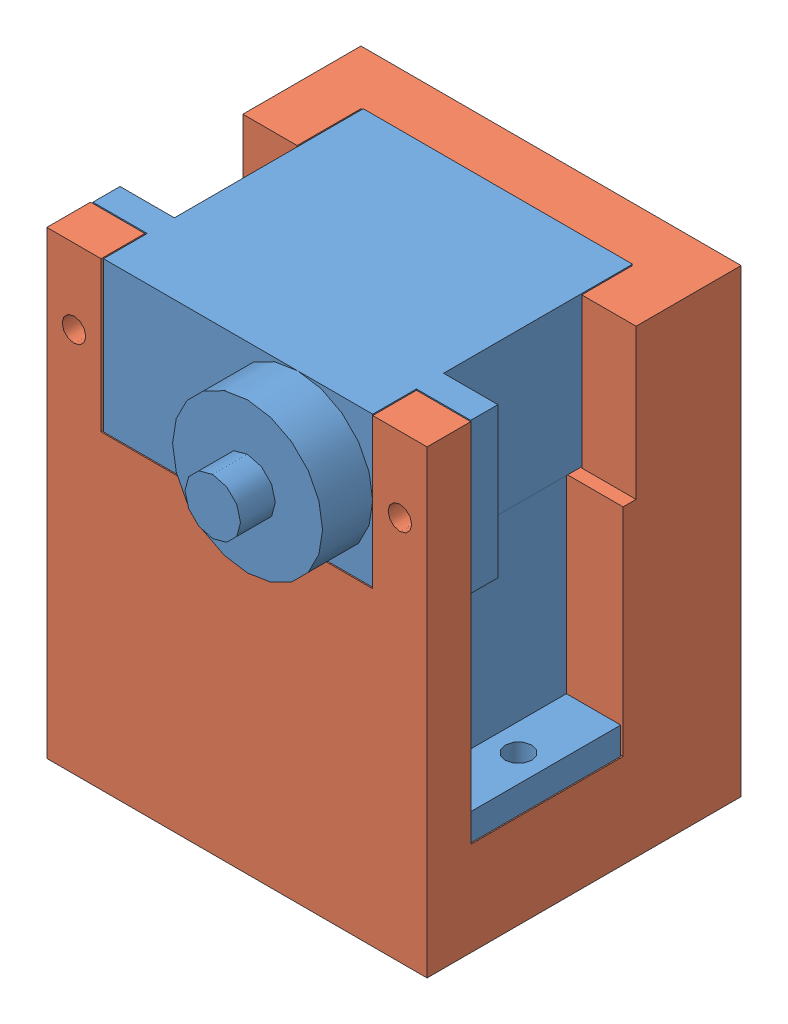
SolidWorks assembly Shoulder, configuration Default. Lengths in mm.
Overall size (32.2 41.9 33.7).
3 component instances, 2 part files, 7 mates.
Components (placement in the parent):
- SG92rMicroServo-1: SG92rMicroServo [Default] at (9.5187 30.2676 26.5439) x (1 0 0) z (0 -1 0) size (32 12.7 29.2)
- SG92rMicroServo-2: SG92rMicroServo [Default] at (9.5187 36.6176 14.5939) size (32 12.7 29.2)
- ShoulderStructure-1: ShoulderStructure [Default] at (14.5687 8.2676 26.5439) size (32.2 38.95 26.6)
Mates (geometry in assembly coordinates):
- Parallel1: parallel anti-aligned: plane of SG92rMicroServo-1 through (9.5187 30.2676 26.5439) normal (0 1 0); plane of SG92rMicroServo-2 through (-1.8813 30.2676 36.5939) normal (0 -1 0)
- Coincident4: coincident aligned: plane of SG92rMicroServo-1 through (-1.8813 8.2676 32.8939) normal (0 0 1); plane of SG92rMicroServo-2 through (9.5187 36.6176 32.8939) normal (0 0 1)
- Coincident5: coincident aligned: plane of SG92rMicroServo-1 through (20.9187 8.2676 20.1939) normal (1 0 0); plane of SG92rMicroServo-2 through (20.9187 30.2676 36.5939) normal (1 0 0)
- Coincident6: coincident anti-aligned: plane of SG92rMicroServo-1 through (9.5187 30.2676 26.5439) normal (0 1 0); plane of SG92rMicroServo-2 through (-1.8813 30.2676 36.5939) normal (0 -1 0)
- Concentric1: concentric aligned: cylinder of SG92rMicroServo-1 through (14.5687 -34.7792 26.5439) axis (0 1 0) radius 2.35; circle of ShoulderStructure-1
- Coincident7: coincident anti-aligned: plane of SG92rMicroServo-1 through (9.5187 8.2676 26.5439) normal (0 -1 0); plane of ShoulderStructure-1 through (14.5687 8.2676 26.5439) normal (0 1 0)
- Parallel2: parallel aligned: plane of SG92rMicroServo-1 through (-1.8813 8.2676 20.1939) normal (-1 0 0); plane of ShoulderStructure-1 through (-6.5813 4.0176 26.5439) normal (-1 0 0)
